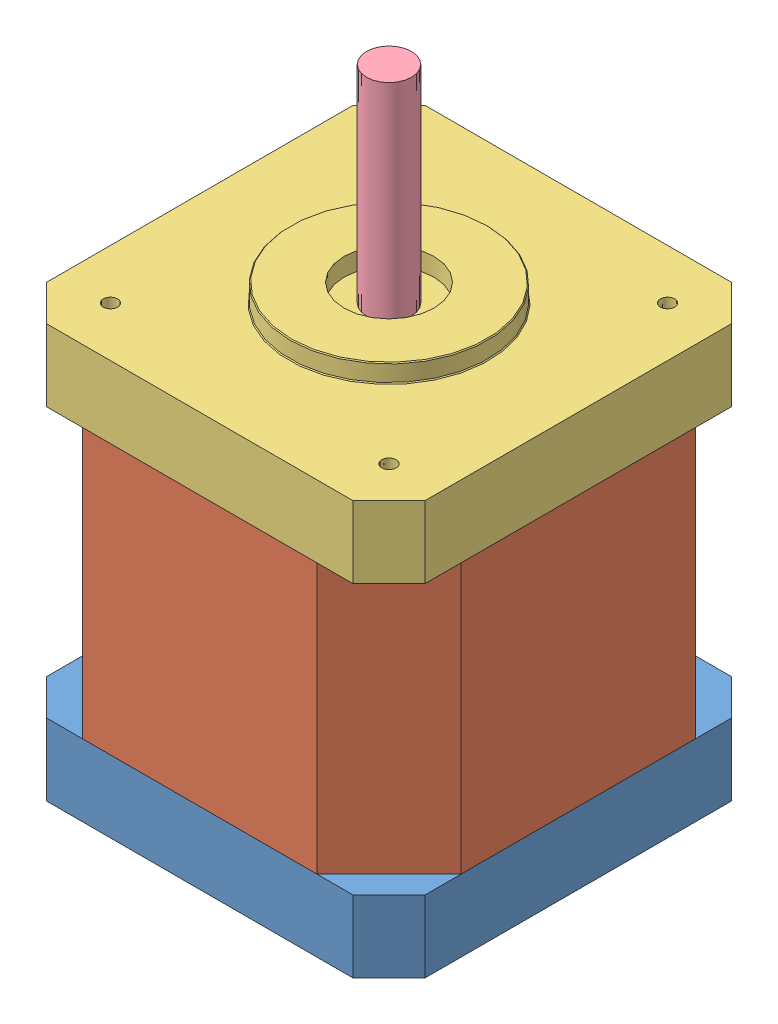
SolidWorks assembly motor, configuration Default. Lengths in mm.
Overall size (42.1 69 42.1).
4 component instances, 4 part files, 10 mates.
Components (placement in the parent):
- bottom plate-1: bottom plate [Default] at origin size (42.1 8 42.1)
- motor-boddy-2: motor-boddy [Default] at (0 8 0) size (42.1 30 42.1)
- motor-top-1: motor-top [Default] at (0 38 0) size (42.1 10 42.1)
- Part4^motor-1: Part4^motor [Default] at (0 46 0) x (1 0 0) z (0 1 0) size (5 5 23) (virtual)
Mates (geometry in assembly coordinates):
- Coincident1: coincident: plane of bottom plate-1 through (0 8 0) normal (0 1 0); point of motor-boddy-2
- Coincident2: coincident anti-aligned: plane of bottom plate-1 through (0 8 0) normal (0 1 0); plane of motor-boddy-2 through (0 8 0) normal (0 -1 0)
- Coincident3: coincident aligned: line of bottom plate-1 through (-21.05 8 -17.05) axis (0 0 1); line of motor-boddy-2 through (-21.05 8 -13.05) axis (0 0 1)
- Coincident4: coincident: line of bottom plate-1 through (17.05 8 -21.05) axis (-1 0 0); moEndPointRef_w of motor-boddy-2
- Coincident5: coincident aligned: line of motor-boddy-2 through (21.05 38 13.05) axis (0 0 -1); line of motor-top-1 through (21.05 38 17.05) axis (0 0 -1)
- Coincident6: coincident aligned: line of motor-boddy-2 through (13.05 38 -21.05) axis (-1 0 0); line of motor-top-1 through (17.05 38 -21.05) axis (-1 0 0)
- InPlace1: in place: plane of motor-top-1 through (0 46 0) normal (0 1 0); plane of Part4^motor-1 through (0 46 0) normal (0 1 0); moOrthogonalPlaneRef_w of motor-top-1 through (0 46 0) normal (0 1 0); plane of Part4^motor-1 through (0 46 0) normal (0 0 -1); plane of motor-top-1 through (0 46 0) normal (0 1 0); plane of Part4^motor-1 through (0 46 0) normal (1 0 0); plane of motor-top-1 through (0 46 0) normal (0 1 0); unknown of Part4^motor-1
- Coincident7: coincident aligned: plane of motor-top-1; plane of Part4^motor-1
- Coincident8: coincident aligned: moOrthogonalPlaneRef_w of motor-top-1 through (0 46 0) normal (0 0 -1); plane of Part4^motor-1 through (0 46 0) normal (0 0 -1)
- Coincident9: coincident anti-aligned: moOrthogonalPlaneRef_w of motor-top-1 through (0 46 0) normal (-1 0 0); plane of Part4^motor-1 through (0 46 0) normal (1 0 0)
